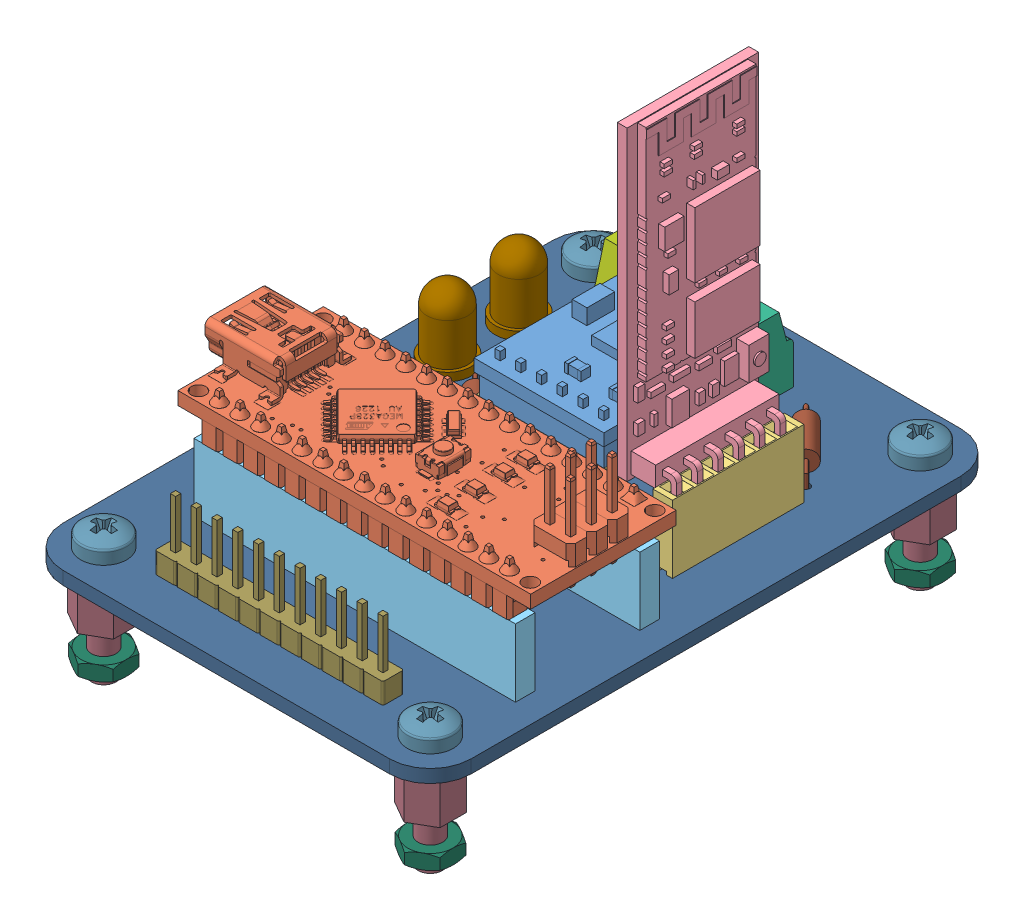
SolidWorks assembly Assembly PCB, configuration Default. Lengths in mm.
Overall size (50 58.6 70).
30 component instances, 15 part files, 60 mates.
Components (placement in the parent):
- DRV8833-1: DRV8833 [Default] at (3 14 -9.5) x (0 0 1) z (-1 0 0) size (18.4 11.9 15.9)
- Arduino Nano-1: Arduino Nano [Default] at (0.3598 23.6638 20.3801) x (-1 0 0) z (0 0 -1) size (44.95 20.74 17.81)
- Header6P-1: Header6P [Default] at (9.35 1.6 -17.1) x (-1 0 0) z (0 1 0) size (16.1 2.4 11.5)
- Header6P-2: Header6P [Default] at (9.35 1.6 -1.9) x (-1 0 0) z (0 1 0) size (16.1 2.4 11.5)
- HC-05-2: HC-05 [Varsayılan] at (11.45 46.6 -1.45) x (0 -1 0) z (1 0 0) size (42.6 16.1 5.9)
- Header6P-3: Header6P [Default] at (17 1.6 -3.15) x (0 0 -1) z (0 1 0) size (16.1 2.4 11.5)
- Header15P-1: Header15P [Default] at (-15.76 2.4 4.86) x (-1 0 0) z (0 1 0) size (39.38 2.4 11.5)
- Header15P-2: Header15P [Default] at (-15.76 2.4 20.0812) x (-1 0 0) z (0 1 0) size (39.38 2.4 11.5)
- ScrewTerminal x 4-1: ScrewTerminal x 4 [Default] at (0 1.6 -26) x (-1 0 0) z (0 0 -1) size (10.62 12 6.3)
- ScrewTerminal x 2-1: ScrewTerminal x 2 [Default] at (-10.48 1.6 -26) x (-1 0 0) z (0 0 -1) size (5.54 12 6.3)
- Push button-1: Push button [Default] at (-18.25 1.6 -2.35) x (0 0 1) z (-1 0 0) size (7.14 7.7 6)
- Led-1: Led [Default] at (-18.5 1.6 -19.33) x (0 0 1) z (-1 0 0) size (5.8 11.9 5.8)
- PCB 50 x 70-3: PCB 50 x 70 [Default] at origin size (50 1.6 70)
- Led-2: Led [Default] at (-18.5 1.6 -10.59) x (0 0 1) z (-1 0 0) size (5.8 11.9 5.8)
- Weerstand-1: Weerstand [Default] at (-10.4645 1.6 -14.4645) x (0.707107 0 -0.707107) z (0.707107 0 0.707107) size (2.5 5.7 10.5)
- Weerstand-2: Weerstand [Default] at (-10.4645 1.6 -5.9645) x (0.707107 0 -0.707107) z (0.707107 0 0.707107) size (2.5 5.7 10.5)
- Weerstand-3: Weerstand [Default] at (13.0355 1.6 -22.9645) x (0.707107 0 -0.707107) z (0.707107 0 0.707107) size (2.5 5.7 10.5)
- Header11P-1: Header11P [Default] at (0 1.6 28.5) size (27.94 11.74 2.54)
- M3 spacer 6 mm-1: M3 spacer 6 mm [Default] at (20 -6 -30) size (5.6 12 6.47)
- M3 spacer 6 mm-2: M3 spacer 6 mm [Default] at (-20 -6 -30) x (0.5 0 0.866025) z (-0.866025 0 0.5) size (5.6 12 6.47)
- M3 spacer 6 mm-3: M3 spacer 6 mm [Default] at (-20 -6 30) x (0.5 0 0.866025) z (-0.866025 0 0.5) size (5.6 12 6.47)
- M3 spacer 6 mm-4: M3 spacer 6 mm [Default] at (20 -6 30) size (5.6 12 6.47)
- pan head cross recess screw_iso-1: pan head cross recess screw_iso [ISO 7045 - M3 x 5 - Z - 5N] at (20 4 30) x (0 -1 0) z (0 0 1) size (7.35 5.6 5.6)
- pan head cross recess screw_iso-2: pan head cross recess screw_iso [ISO 7045 - M3 x 5 - Z - 5N] at (20 4 -30) x (0 -1 0) z (0 0 1) size (7.35 5.6 5.6)
- pan head cross recess screw_iso-3: pan head cross recess screw_iso [ISO 7045 - M3 x 5 - Z - 5N] at (-20 4 30) x (0 -1 0) z (0 0 1) size (7.35 5.6 5.6)
- pan head cross recess screw_iso-4: pan head cross recess screw_iso [ISO 7045 - M3 x 5 - Z - 5N] at (-20 4 -30) x (0 -1 0) z (0 0 1) size (7.35 5.6 5.6)
- hex thin nut chamfered gradeab_iso-1: hex thin nut chamfered gradeab_iso [ISO - 4035 - M3 - N] at (20 -10.8 -30) x (1 0 0) z (0 -1 0) size (5.5 6.35 1.8)
- hex thin nut chamfered gradeab_iso-2: hex thin nut chamfered gradeab_iso [ISO - 4035 - M3 - N] at (20 -10.8 30) x (1 0 0) z (0 -1 0) size (5.5 6.35 1.8)
- hex thin nut chamfered gradeab_iso-3: hex thin nut chamfered gradeab_iso [ISO - 4035 - M3 - N] at (-20 -10.8 30) x (0.5 0 -0.866025) z (0 -1 0) size (5.5 6.35 1.8)
- hex thin nut chamfered gradeab_iso-4: hex thin nut chamfered gradeab_iso [ISO - 4035 - M3 - N] at (-20 -10.8 -30) x (1 0 0) z (0 -1 0) size (5.5 6.35 1.8)
Mates (geometry in assembly coordinates):
- ProfileCenter6: profile center = 5.6 mm aligned: plane of DRV8833-1 through (3 4 -9.5) normal (0 -1 0); plane of Header6P-1 through (-3.525 -1.6 -17.1) normal (0 -1 0)
- ProfileCenter7: profile center = 5.6 mm aligned: plane of Header6P-2 through (-3.525 -1.6 -1.9) normal (0 -1 0); plane of DRV8833-1 through (3 4 -9.5) normal (0 -1 0)
- ProfileCenter9: profile center = 5.6 mm aligned: plane of HC-05-2 through (11.45 4 -1.45) normal (0 -1 0); plane of Header6P-3 through (17 -1.6 -16.025) normal (0 -1 0)
- ProfileCenter10: profile center = 3.5 mm aligned: plane of Header15P-1 through (-15.76 -1.6 4.86) normal (0 -1 0); plane of Arduino Nano-1 through (-15.76 1.9 4.86) normal (0 -1 0)
- ProfileCenter11: profile center = 3.5 mm aligned: plane of Header15P-2 through (-15.76 -1.6 20.0812) normal (0 -1 0); plane of Arduino Nano-1 through (-15.76 1.9 20.0812) normal (0 -1 0)
- Coincident2: coincident aligned: plane of PCB 50 x 70-3 through (0 0 0) normal (0 1 0)
- Coincident3: coincident aligned: plane of PCB 50 x 70-3 through (0 0 0) normal (0 0 1)
- Coincident4: coincident aligned: plane of PCB 50 x 70-3 through (0 0 0) normal (1 0 0)
- ProfileCenter12: profile center = 3.2 mm anti-aligned: plane of Header15P-1 through (-15.76 -1.6 4.86) normal (0 -1 0); circle of PCB 50 x 70-3
- Parallel5: parallel aligned: plane of Header15P-2 through (-14.49 9.1 21.2812) normal (0 0 1); plane of PCB 50 x 70-3 through (-25 1.6 35) normal (0 0 1)
- ProfileCenter14: profile center = 3.2 mm anti-aligned: plane of Header6P-3 through (17 -1.6 -3.325) normal (0 -1 0); circle of PCB 50 x 70-3
- Parallel6: parallel aligned: plane of Header6P-3 through (18.2 1.6 -1.65) normal (1 0 0); plane of PCB 50 x 70-3 through (25 1.6 35) normal (1 0 0)
- ProfileCenter15: profile center = 3.2 mm anti-aligned: circle of PCB 50 x 70-3; plane of Header6P-1 through (-3.525 -1.6 -17.1) normal (0 -1 0)
- Parallel7: parallel aligned: plane of Header6P-1 through (10.85 1.6 -18.3) normal (0 0 -1); plane of PCB 50 x 70-3 through (-25 1.6 -35) normal (0 0 -1)
- ProfileCenter16: profile center = 3.2 mm anti-aligned: plane of ScrewTerminal x 4-1 through (0 -1.6 -26) normal (0 -1 0); circle of PCB 50 x 70-3
- Parallel9: parallel aligned: plane of ScrewTerminal x 4-1 through (5.31 10.4 -29.15) normal (1 0 0); plane of PCB 50 x 70-3 through (25 1.6 35) normal (1 0 0)
- ProfileCenter17: profile center = 3.2 mm anti-aligned: plane of ScrewTerminal x 2-1 through (-10.48 -1.6 -26) normal (0 -1 0); circle of PCB 50 x 70-3
- Parallel10: parallel aligned: plane of ScrewTerminal x 2-1 through (-13.25 10.4 -29.15) normal (-1 0 0); plane of PCB 50 x 70-3 through (-25 1.6 35) normal (-1 0 0)
- ProfileCenter18: profile center = 3.2 mm aligned: plane of Led-2 through (-18.5 -1.6 -11.86) normal (0 -1 0); circle of PCB 50 x 70-3
- ProfileCenter19: profile center = 3.2 mm aligned: plane of Led-1 through (-18.5 -1.6 -20.6) normal (0 -1 0); circle of PCB 50 x 70-3
- Coincident12: coincident aligned: plane of Led-1 through (-18.5 1.6 -19.33) normal (-1 0 0); plane of Led-2 through (-18.5 1.6 -10.59) normal (-1 0 0)
- ProfileCenter20: profile center = 3.2 mm anti-aligned: plane of Push button-1 through (-18.25 -1.6 -2.35) normal (0 -1 0); circle of PCB 50 x 70-3
- Parallel12: parallel aligned: plane of Push button-1 through (-21.25 4.6 -5.35) normal (-1 0 0); plane of PCB 50 x 70-3 through (-25 1.6 35) normal (-1 0 0)
- ProfileCenter22: profile center = 3.2 mm aligned: plane of Weerstand-1 through (-14 -1.6 -18) normal (0 -1 0); circle of PCB 50 x 70-3
- ProfileCenter23: profile center = 3.2 mm aligned: plane of Weerstand-2 through (-14 -1.6 -9.5) normal (0 -1 0); circle of PCB 50 x 70-3
- ProfileCenter24: profile center = 3.2 mm aligned: plane of Weerstand-3 through (9.5 -1.6 -26.5) normal (0 -1 0); circle of PCB 50 x 70-3
- Parallel14: parallel aligned: plane of Weerstand-1 through (-10.4645 1.6 -14.4645) normal (0.707107 0 -0.707107); plane of Weerstand-2 through (-10.4645 1.6 -5.9645) normal (0.707107 0 -0.707107)
- Parallel15: parallel aligned: plane of Weerstand-2 through (-10.4645 1.6 -5.9645) normal (0.707107 0 -0.707107); plane of Weerstand-3 through (13.0355 1.6 -22.9645) normal (0.707107 0 -0.707107)
- Angle1: planar angle = 0.785398 rad aligned: plane of Weerstand-1 through (-10.4645 1.6 -14.4645) normal (0.707107 0 -0.707107)
- Coincident13: coincident aligned: plane of M3 spacer 6 mm-1 through (20 0 -30) normal (0 1 0); plane of M3 spacer 6 mm-2 through (-20 0 -30) normal (0 1 0)
- Coincident14: coincident aligned: plane of M3 spacer 6 mm-3 through (-20 0 30) normal (0 1 0); plane of M3 spacer 6 mm-4 through (20 0 30) normal (0 1 0)
- Coincident15: coincident aligned: plane of M3 spacer 6 mm-2 through (-20 0 -30) normal (0 1 0); plane of M3 spacer 6 mm-3 through (-20 0 30) normal (0 1 0)
- Concentric1: concentric aligned: cylinder of PCB 50 x 70-3 through (-20 -4.5255 30) axis (0 1 0) radius 1.6; cylinder of M3 spacer 6 mm-3 through (-20 -4 30) axis (0 1 0) radius 1.5
- Concentric2: concentric aligned: cylinder of PCB 50 x 70-3 through (20 -4.5255 30) axis (0 1 0) radius 1.6; cylinder of M3 spacer 6 mm-4 through (20 -4 30) axis (0 1 0) radius 1.5
- Concentric3: concentric aligned: cylinder of PCB 50 x 70-3 through (-20 -4.5255 -30) axis (0 1 0) radius 1.6; cylinder of M3 spacer 6 mm-2 through (-20 -4 -30) axis (0 1 0) radius 1.5
- Concentric4: concentric aligned: cylinder of PCB 50 x 70-3 through (20 -4.5255 -30) axis (0 1 0) radius 1.6; cylinder of M3 spacer 6 mm-1 through (20 -4 -30) axis (0 1 0) radius 1.5
- Coincident16: coincident aligned: plane of M3 spacer 6 mm-2 through (-22.8 0 -31.6166) normal (-1 0 0); plane of M3 spacer 6 mm-3 through (-22.8 0 28.3834) normal (-1 0 0)
- Coincident17: coincident aligned: plane of M3 spacer 6 mm-1 through (17.2 0 -31.6166) normal (-1 0 0); plane of M3 spacer 6 mm-4 through (17.2 0 28.3834) normal (-1 0 0)
- Coincident19: coincident anti-aligned: plane of PCB 50 x 70-3 through (0 0 0) normal (0 -1 0); plane of M3 spacer 6 mm-3 through (-20 0 30) normal (0 1 0)
- Coincident21: coincident aligned: plane of pan head cross recess screw_iso-1 through (21.5 1.6 30) normal (0 -1 0); plane of pan head cross recess screw_iso-4 through (-18.5 1.6 -30) normal (0 -1 0)
- Coincident22: coincident aligned: plane of pan head cross recess screw_iso-2 through (21.5 1.6 -30) normal (0 -1 0); plane of pan head cross recess screw_iso-4 through (-18.5 1.6 -30) normal (0 -1 0)
- Coincident23: coincident aligned: plane of pan head cross recess screw_iso-2 through (21.5 1.6 -30) normal (0 -1 0); plane of pan head cross recess screw_iso-3 through (-18.5 1.6 30) normal (0 -1 0)
- Coincident24: coincident anti-aligned: plane of PCB 50 x 70-3 through (0 1.6 0) normal (0 1 0); plane of pan head cross recess screw_iso-3 through (-18.5 1.6 30) normal (0 -1 0)
- Concentric5: concentric aligned: cylinder of PCB 50 x 70-3 through (-20 -4.5255 30) axis (0 1 0) radius 1.6; cylinder of pan head cross recess screw_iso-3 through (-20 29.4 30) axis (0 1 0) radius 1.5
- Concentric6: concentric aligned: cylinder of PCB 50 x 70-3 through (-20 -4.5255 -30) axis (0 1 0) radius 1.6; cylinder of pan head cross recess screw_iso-4 through (-20 29.4 -30) axis (0 1 0) radius 1.5
- Concentric7: concentric aligned: cylinder of PCB 50 x 70-3 through (20 -4.5255 30) axis (0 1 0) radius 1.6; cylinder of pan head cross recess screw_iso-1 through (20 29.4 30) axis (0 1 0) radius 1.5
- Concentric8: concentric aligned: cylinder of PCB 50 x 70-3 through (20 -4.5255 -30) axis (0 1 0) radius 1.6; cylinder of pan head cross recess screw_iso-2 through (20 29.4 -30) axis (0 1 0) radius 1.5
- Coincident25: coincident aligned: plane of pan head cross recess screw_iso-3 through (-19.63 2.25 30.5275) normal (-1 0 0); plane of pan head cross recess screw_iso-4 through (-19.63 2.25 -29.4725) normal (-1 0 0)
- Coincident26: coincident aligned: plane of pan head cross recess screw_iso-1 through (20.37 2.25 30.5275) normal (-1 0 0); plane of pan head cross recess screw_iso-2 through (20.37 2.25 -29.4725) normal (-1 0 0)
- Coincident28: coincident aligned: plane of hex thin nut chamfered gradeab_iso-2 through (20 -10.8 33.1754) normal (0 -1 0); plane of hex thin nut chamfered gradeab_iso-4 through (-20 -10.8 -26.8246) normal (0 -1 0)
- Coincident29: coincident aligned: plane of hex thin nut chamfered gradeab_iso-1 through (20 -10.8 -26.8246) normal (0 -1 0); plane of hex thin nut chamfered gradeab_iso-2 through (20 -10.8 33.1754) normal (0 -1 0)
- Coincident30: coincident aligned: plane of hex thin nut chamfered gradeab_iso-1 through (20 -10.8 -26.8246) normal (0 -1 0); plane of hex thin nut chamfered gradeab_iso-3 through (-17.25 -10.8 31.5877) normal (0 -1 0)
- Concentric9: concentric anti-aligned: cylinder of M3 spacer 6 mm-3 through (-20 -12 30) axis (0 1 0) radius 1.5; cylinder of hex thin nut chamfered gradeab_iso-3 through (-20 -9 30) axis (0 -1 0) radius 1.25
- Concentric10: concentric anti-aligned: cylinder of M3 spacer 6 mm-2 through (-20 -12 -30) axis (0 1 0) radius 1.5; cylinder of hex thin nut chamfered gradeab_iso-4 through (-20 -9 -30) axis (0 -1 0) radius 1.25
- Concentric11: concentric anti-aligned: cylinder of M3 spacer 6 mm-4 through (20 -12 30) axis (0 1 0) radius 1.5; cylinder of hex thin nut chamfered gradeab_iso-2 through (20 -9 30) axis (0 -1 0) radius 1.25
- Concentric12: concentric anti-aligned: cylinder of M3 spacer 6 mm-1 through (20 -12 -30) axis (0 1 0) radius 1.5; cylinder of hex thin nut chamfered gradeab_iso-1 through (20 -9 -30) axis (0 -1 0) radius 1.25
- Coincident32: coincident aligned: plane of hex thin nut chamfered gradeab_iso-3 through (-22.75 -9 31.5877) normal (-1 0 0); plane of hex thin nut chamfered gradeab_iso-4 through (-22.75 -9 -28.4123) normal (-1 0 0)
- Coincident33: coincident aligned: plane of hex thin nut chamfered gradeab_iso-1 through (17.25 -9 -28.4123) normal (-1 0 0); plane of hex thin nut chamfered gradeab_iso-2 through (17.25 -9 31.5877) normal (-1 0 0)
- Distance1: distance = 3 mm anti-aligned: plane of hex thin nut chamfered gradeab_iso-3 through (-17.25 -9 31.5877) normal (0 1 0); plane of M3 spacer 6 mm-3 through (-20 -6 30) normal (0 -1 0)
- ProfileCenter28: profile center = 3.2 mm: plane of Header11P-1 through (0 -1.6 28.5) normal (0 -1 0); circle of PCB 50 x 70-3
